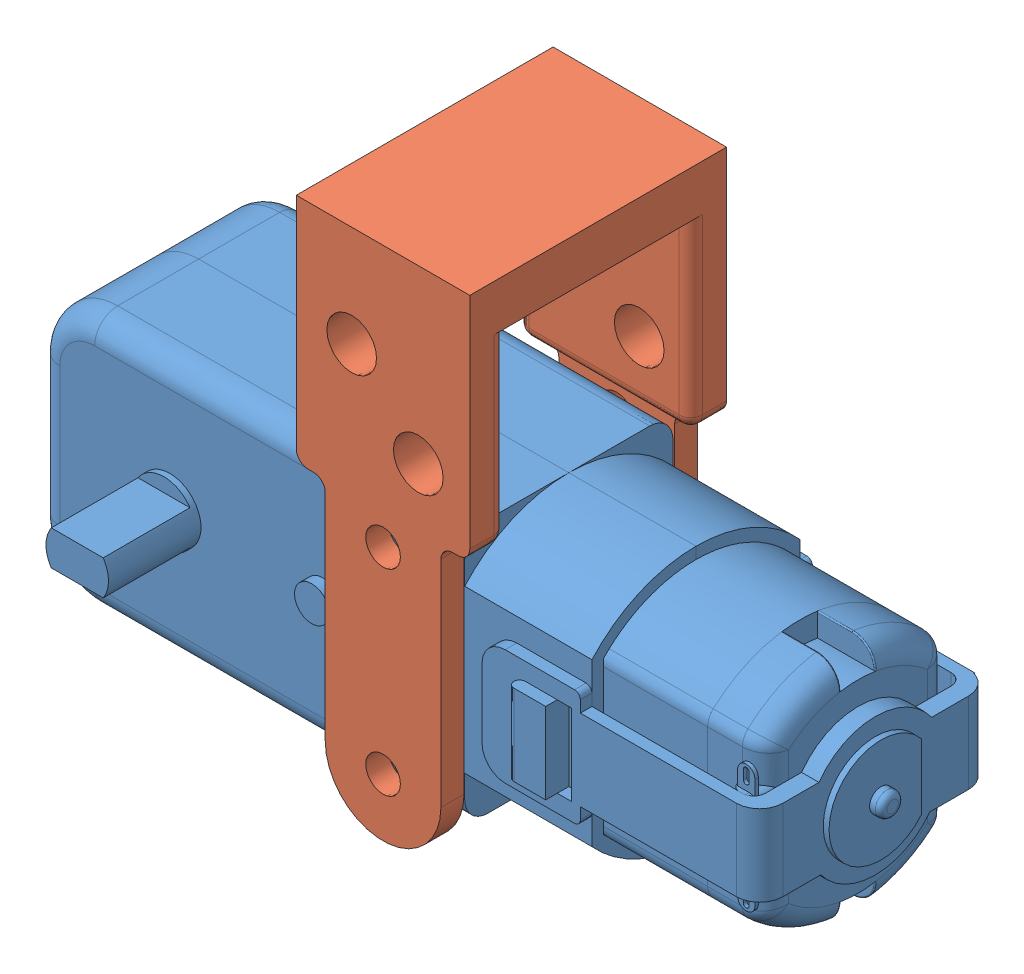
SolidWorks assembly DudukanMotor, configuration Default. Lengths in mm.
Overall size (70 44.6 34.5).
2 component instances, 2 part files, 4 mates.
Components (placement in the parent):
- Motor DC-1: Motor DC [Default] at (20.191 61.1021 29.6752) size (70 22 34.5)
- DudukanMotor-1: DudukanMotor [Default] at (20.191 61.1021 71.3311) size (15 44.6 22.2)
Mates (geometry in assembly coordinates):
- InPlace1: in place: plane of Motor DC-1 through (2.9984 33.2728 71.3311) normal (0 0 1); plane of ? through (0 0 71.3311) normal (0 0 1); moOrthogonalPlaneRef_w of Motor DC-1 through (2.9984 33.2728 71.3311) normal (0 0 1); plane of ? through (0 0 71.3311) normal (0 1 0); plane of Motor DC-1 through (2.9984 33.2728 71.3311) normal (0 0 1); plane of ? through (0 0 71.3311) normal (1 0 0); plane of Motor DC-1 through (2.9984 33.2728 71.3311) normal (0 0 1); unknown of DudukanMotor-1
- Coincident1: coincident aligned: plane of ?; plane of ?
- Coincident2: coincident aligned: moOrthogonalPlaneRef_w of Motor DC-1 through (20.191 61.1021 71.3311) normal (0 1 0); plane of Part10^Assem4-1 through (20.191 61.1021 71.3311) normal (0 1 0)
- Coincident3: coincident anti-aligned: moOrthogonalPlaneRef_w of Motor DC-1 through (20.191 61.1021 71.3311) normal (-1 0 0); plane of Part10^Assem4-1 through (20.191 61.1021 71.3311) normal (1 0 0)
